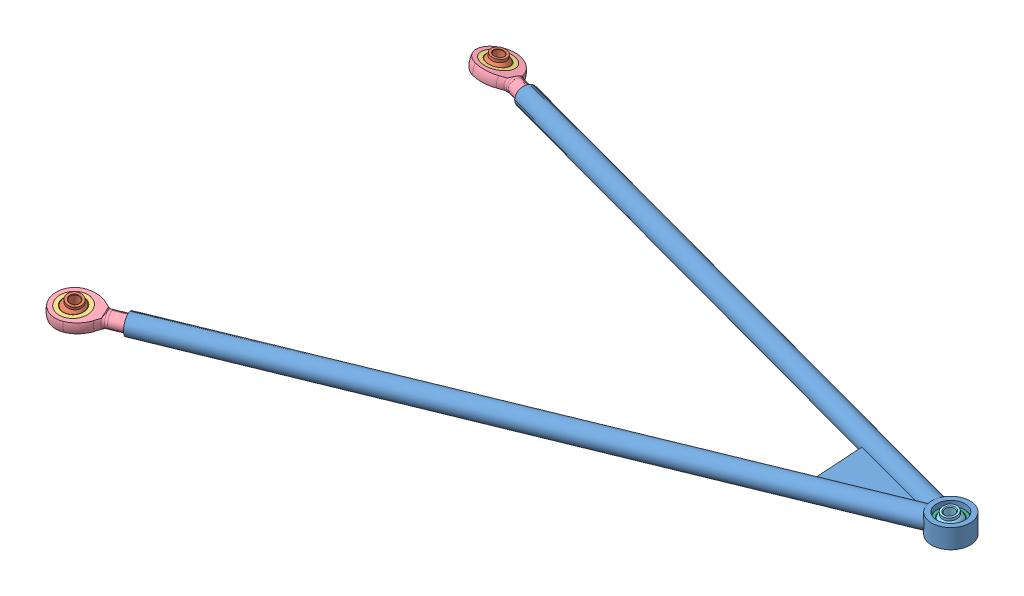
SolidWorks assembly Front Bottom Wishbone, configuration Default. Lengths in mm.
Overall size (443.93 49.22 333.22).
12 component instances, 6 part files, 6 mates.
Components (placement in the parent):
- Front Bottom Wishbone-1: Front Bottom Wishbone [Default<As Machined>] at (324.0376 211.8292 451.2077) size (400.69 13.56 273.63)
- HXAM-4T Rod End-1: HXAM-4T Rod End [Default] at (-87.2892 211.8292 339.8272) x (0.871339 -0.04183 0.488895) z (-0.481454 0.119437 0.868295) size (69.29 33.12 43.73) (flexible)
  - HXAM-4T Ball-1: HXAM-4T Ball [Default] at (0 0 -49.2252) size (15.06 15.06 15.06)
  - HXAM-4T Sleeve-1: HXAM-4T Sleeve [Default] at (47.691 3.4203 -11.7043) x (0.229693 0.107437 0.967315) z (-0.968833 -0.069484 0.237771) size (19.53 6.73 19.53)
  - HXAM-4T Housing-1: HXAM-4T Housing [Default] at (47.691 3.4203 -11.7043) x (0.229693 0.107437 0.967315) z (-0.968833 -0.069484 0.237771) size (27.48 26.04 62.51)
- HXAM-4T Rod End-2: HXAM-4T Rod End [Default] at (-87.2892 211.8292 619.2272) x (0.939661 -0.134099 -0.314729) z (0.292481 -0.162313 0.942396) size (67.24 35.42 34.35) (flexible)
  - HXAM-4T Ball-1: HXAM-4T Ball [Default] at (0 0 -49.2252) size (15.06 15.06 15.06)
  - HXAM-4T Sleeve-1: HXAM-4T Sleeve [Default] at (48.6788 5.9778 -4.2139) x (0.07686 0.074951 0.994221) z (-0.988901 -0.121438 0.085604) size (19.53 6.73 19.53)
  - HXAM-4T Housing-1: HXAM-4T Housing [Default] at (48.6788 5.9778 -4.2139) x (0.07686 0.074951 0.994221) z (-0.988901 -0.121438 0.085604) size (27.48 26.04 62.51)
- HAB-4T Bearing-1: HAB-4T Bearing [Default] at (324.0376 211.8292 451.2077) x (0.99961 -0.025535 -0.011345) z (0.007988 -0.127901 0.991755) size (19.36 15.06 19.93) (flexible)
  - HAB-4T Ball-1: HAB-4T Ball [Default] at origin size (15.06 15.06 15.06)
  - HAB-4T Cup-1: HAB-4T Cup [Default] x (0.999437 0.022532 -0.024877) z (0.021783 0.128464 0.991475) size (18.8 6.48 18.8)
Mates (geometry in assembly coordinates):
- Concentric1: concentric anti-aligned: cylinder of Front Bottom Wishbone-1 through (324.0376 218.6068 451.2077) axis (0 -1 0) radius 9.3345; cylinder of HAB-4T Bearing-1/HAB-4T Cup-1 through (324.0376 211.8292 451.2077) axis (0 1 0) radius 9.398
- Coincident1: coincident anti-aligned: plane of Front Bottom Wishbone-1 through (324.0376 208.5907 451.2077) normal (0 1 0); plane of HAB-4T Bearing-1/HAB-4T Cup-1 through (324.0376 208.5907 451.2077) normal (0 -1 0)
- Concentric2: concentric anti-aligned: cylinder of Front Bottom Wishbone-1 through (324.0376 211.8292 451.2077) axis (-0.925744 0 0.37815) radius 6.35; cylinder of HXAM-4T Rod End-2/HXAM-4T Housing-1 through (-55.9675 211.8292 606.4329) axis (0.925744 0 -0.37815) radius 4.7625
- Concentric3: concentric aligned: cylinder of Front Bottom Wishbone-1 through (-60.4552 211.8292 347.0934) axis (0.965239 0 0.261371) radius 6.35; cylinder of ? through (-54.6312 211.8292 348.6704) axis (0.965239 0 0.261371) radius 4.7625
- Coincident2: coincident: point of Front Bottom Wishbone-1; point of HXAM-4T Rod End-2/HXAM-4T Ball-1
- Coincident3: coincident: point of Front Bottom Wishbone-1; point of HXAM-4T Rod End-1/HXAM-4T Ball-1
